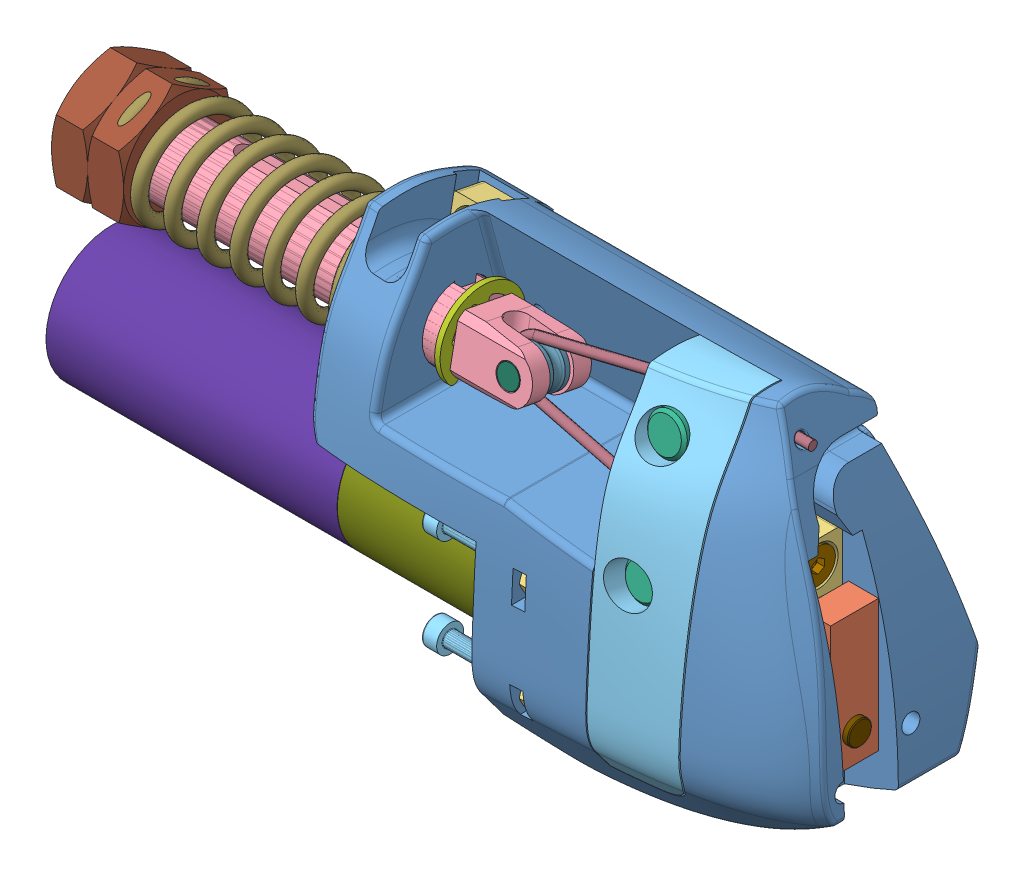
SolidWorks assembly a-antriebstrang-amax22-v05, configuration 01. Lengths in mm.
Overall size (136.53 64.51 41.42).
40 component instances, 22 part files, 63 mates.
Components (placement in the parent):
- a-motorträger-v01-1: a-motorträger-v01 [01] x (-1 0 0) z (0 0 -1) size (130.38 64.51 41.42)
  - p-halterreferenz-v02-1: p-halterreferenz-v02 [01] at (-8 0 0) x (0 0 -1) z (1 0 0) size (41.19 64.51 84.36)
  - z-jfm-0608-06-v01-1: z-jfm-0608-06-v01 [01] at (-23.3 0 0) x (-1 0 0) z (0 0 -1) size (6 12 12)
  - z-induktiv-sensor-v01-1: z-induktiv-sensor-v01 [01] at (29 21.9082 7.6275) x (1 0 0) z (0 0.190809 -0.981627) size (8 16 4.7)
  - z-induktiv-sensor-v01-2: z-induktiv-sensor-v01 [01] at (-25.5 8.63 4) x (0 0 -1) z (-1 0 0) size (8 16 4.7)
  - p-federstössel-v01-1: p-federstössel-v01 [01] at (77.9 27.8 -1.72) x (-1 0 0) z (0 -0.190809 0.981627) size (77 12 12)
  - p-halterdeckel-v01-1: p-halterdeckel-v01 [01] at (-8 0 0) x (0 0 -1) z (1 0 0) size (29.44 55.93 14.71)
  - z-passschraube-misumi-4-v01-1: z-passschraube-misumi-4-v01 [01] at (-13.1 35.2829 -8.5672) x (0 -0.190809 0.981627) z (-0.839411 -0.533511 -0.103704) size (18 6.5 6.5)
  - z-passschraube-misumi-4-v01-2: z-passschraube-misumi-4-v01 [01] at (-13.1 16.1412 -12.288) x (0 -0.190809 0.981627) z (-0.58333 0.797312 0.154982) size (18 6.5 6.5)
  - lock washer for shafts_din-3: lock washer for shafts_din [Lock washer DIN 6799 - 7] at (24 27.8 -1.72) x (0 0 1) z (-1 0 0) size (14.3 11.94 0.9)
  - hex nut style 1 gradeab_din-3: hex nut style 1 gradeab_din [Hexagon Nut ISO 4032 - M2.5 - W - N] at (-13.1 31.8991 8.8409) x (1 0 0) z (0 -0.190809 0.981627) size (5 5.77 2)
  - hex nut style 1 gradeab_din-4: hex nut style 1 gradeab_din [Hexagon Nut ISO 4032 - M2.5 - W - N] at (-13.1 12.7574 5.1202) x (1 0 0) z (0 -0.190809 0.981627) size (5 5.77 2)
  - socket countersunk head screw_din-3: socket countersunk head screw_din [DIN 7991 - M3 x 8 --- 4.8C] at (-30.15 20.63 0) size (8 5.7 5.7)
  - socket countersunk head screw_din-4: socket countersunk head screw_din [DIN 7991 - M3 x 8 --- 4.8C] at (33 34.5749 5.3527) x (0 -0.190809 0.981627) z (-0.981627 0.187303 0.036408) size (8 5.7 5.7)
  - p-oese-v01-1: p-oese-v01 [01] at (-25.5 37.4 0) size (3.5 4 4)
  - hex thin nut chamfered gradeab_din-3: hex thin nut chamfered gradeab_din [Hexagon Thin Nut ISO 4035 - M12 - N] at (74.9 27.8 -1.72) x (0 -0.006521 -0.999979) z (-1 0 0) size (18 20.78 6)
  - hex thin nut chamfered gradeab_din-4: hex thin nut chamfered gradeab_din [Hexagon Thin Nut ISO 4035 - M12 - N] at (80.9 27.8 -1.72) x (0 0 1) z (-1 0 0) size (18 20.78 6)
  - z-feder-febrotec-v01-1: z-feder-febrotec-v01 [01] at (40 28.171 -1.6479) x (1 0 0) z (0 -0.190809 0.981627) size (40.25 20.98 20.5)
  - p-seil-v02-1: p-seil-v02 [01] at (-16.85 -0.1381 -7.1506) x (-1 0 0) z (0 0.190809 -0.981627) size (48.5 39 1.5)
  - p-umlenkpulley-v06-1: p-umlenkpulley-v06 [01] at (-13.1 33.728 -0.5677) x (0 -0.190809 0.981627) z (-0.981627 0.187303 0.036408) size (3.6 7.15 7.15)
  - p-umlenkpulley-v06-4: p-umlenkpulley-v06 [01] at (-13.1 14.5863 -4.2885) x (0 -0.190809 0.981627) z (-0.997632 0.067518 0.013124) size (3.6 7.15 7.15)
  - p-umlenkpulley-v06-3: p-umlenkpulley-v06 [01] at (14.9 27.8 -1.72) x (0 -0.190809 0.981627) z (-0.981627 0.187303 0.036408) size (3.6 7.15 7.15)
  - parallel pin unhardened_din-3: parallel pin unhardened_din [Parallel Pin ISO 2338 - 4 h6 x 10 - St] at (14.9 28.754 -6.6281) x (0 -0.190809 0.981627) z (-0.981627 0.187303 0.036408) size (10 4 4)
- z-ec-amax22-gp22-c-v01-2: z-ec-amax22-gp22-c-v01 [01] x (-1 0 0) z (0 -0.173648 -0.984808) size (108.9 22 22)
  - z-getriebe-gp22c-v01-1: z-getriebe-gp22c-v01 [Standard] at origin size (53.85 22 22)
  - z-EC-max22-283856-v01-1: z-EC-max22-283856-v01 [01] at (39.05 0 0) size (65 22 22)
- p-motorpulley-v03-2: p-motorpulley-v03 [01] at (3.15 0 0) x (1 0 0) z (0 -0.173648 -0.984808) size (34 9 9)
- socket set screw flat point_din-2: socket set screw flat point_din [DIN 913 - M2 x 3-C] at (10.15 -0.7814 -4.4316) x (0 0.173648 0.984808) z (1 0 0) size (3 2 2)
- p-absolutmess-plättchen-v01-2: p-absolutmess-plättchen-v01 [01] at (36.2 0 0) x (0 0 1) z (-1 0 0) size (8 22 5)
- hex thin nut chamfered gradeab_din-6: hex thin nut chamfered gradeab_din [Hexagon Thin Nut ISO 4035 - M2.5 - C] at (-4 9 13) x (0 -0.5 0.866025) z (-1 0 0) size (5 5.77 1.6)
- hex thin nut chamfered gradeab_din-7: hex thin nut chamfered gradeab_din [Hexagon Thin Nut ISO 4035 - M2.5 - C] at (-4 -7.5 -13) x (0 0.5 0.866025) z (-1 0 0) size (5 5.77 1.6)
- hex thin nut chamfered gradeab_din-8: hex thin nut chamfered gradeab_din [Hexagon Thin Nut ISO 4035 - M2.5 - C] at (-4 9 -13) x (0 -0.5 0.866025) z (-1 0 0) size (5 5.77 1.6)
- hex thin nut chamfered gradeab_din-9: hex thin nut chamfered gradeab_din [Hexagon Thin Nut ISO 4035 - M2.5 - C] at (-4 -7.5 13) x (0 -1 0) z (-1 0 0) size (5 5.77 1.6)
- countersunk slotted raised head screw_din-5: countersunk slotted raised head screw_din [ISO 2010 - M2.5 x 10 --- 10C] at (9 6.5778 2.3941) x (-1 0 0) z (0 -0.859497 -0.51114) size (10.59 4.7 4.66)
- countersunk slotted raised head screw_din-6: countersunk slotted raised head screw_din [ISO 2010 - M2.5 x 10 --- 10C] at (9 -5.3623 4.4995) x (-1 0 0) z (0 -0.924225 -0.381849) size (10.59 4.7 4.66)
- countersunk slotted raised head screw_din-7: countersunk slotted raised head screw_din [ISO 2010 - M2.5 x 10 --- 10C] at (9 -1.2155 -6.8937) x (-1 0 0) z (0 -0.959089 0.283105) size (10.59 4.7 4.66)
- socket head cap screw_din-2: socket head cap screw_din [DIN 912 M2.5 x 16 --- 16C] at (-20.7 9 -13) size (18.5 4.5 4.5)
- socket head cap screw_din-3: socket head cap screw_din [DIN 912 M2.5 x 16 --- 16C] at (-20.7 -7.5 -13) x (1 0 0) z (0 -0.70701 -0.707203) size (18.5 4.5 4.5)
- socket head cap screw_din-4: socket head cap screw_din [DIN 912 M2.5 x 16 --- 16C] at (-20.7 9 13) size (18.5 4.5 4.5)
- socket head cap screw_din-5: socket head cap screw_din [DIN 912 M2.5 x 16 --- 16C] at (-20.7 -7.5 13) size (18.5 4.5 4.5)
Mates (geometry in assembly coordinates):
- Konzentrisch1: concentric aligned: cylinder of a-motorträger-v01-1/p-halterreferenz-v02-1 through (0 0 0) axis (-1 0 0) radius 11.5; cylinder of z-ec-amax22-gp22-c-v01-2/z-getriebe-gp22c-v01-1 through (-1.6 0 0) axis (-1 0 0) radius 11
- Deckungsgleich1: coincident anti-aligned: plane of a-motorträger-v01-1/p-halterreferenz-v02-1 through (0 0 0) normal (-1 0 0); plane of z-ec-amax22-gp22-c-v01-2/z-getriebe-gp22c-v01-1 through (0 -1.9101 -10.8329) normal (1 0 0)
- Deckungsgleich2: coincident anti-aligned: plane of a-motorträger-v01-1 through (0 0 0) normal (0 0 -1); plane of assembly through (0 0 0) normal (0 0 1)
- Deckungsgleich3: coincident aligned: plane of a-motorträger-v01-1; plane of assembly through (0 0 0) normal (0 1 0)
- Deckungsgleich4: coincident anti-aligned: plane of a-motorträger-v01-1 through (0 0 0) normal (-1 0 0); plane of assembly through (0 0 0) normal (1 0 0)
- Konzentrisch2: concentric anti-aligned: cylinder of z-ec-amax22-gp22-c-v01-2/z-getriebe-gp22c-v01-1 through (3.15 0 0) axis (1 0 0) radius 2; cylinder of p-motorpulley-v03-2 through (3.15 0 0) axis (-1 0 0) radius 2
- Deckungsgleich5: coincident anti-aligned: plane of z-ec-amax22-gp22-c-v01-2/z-getriebe-gp22c-v01-1 through (3.15 -3.4468 0.6078) normal (1 0 0); plane of p-motorpulley-v03-2 through (3.15 -4.4316 0.7814) normal (-1 0 0)
- Konzentrisch3: concentric anti-aligned: cylinder of p-motorpulley-v03-2 through (10.15 0 0) axis (0 0.173648 0.984808) radius 0.8; cylinder of socket set screw flat point_din-2 through (10.15 -2.9867 -16.9387) axis (0 -0.173648 -0.984808) radius 1
- Parallel2: parallel aligned: plane of z-ec-amax22-gp22-c-v01-2/z-getriebe-gp22c-v01-1 through (14.85 1.0423 -1.7069) normal (0 -0.173648 -0.984808); plane of p-motorpulley-v03-2 through (3.15 0 0) normal (0 -0.173648 -0.984808)
- Deckungsgleich7: coincident anti-aligned: plane of z-ec-amax22-gp22-c-v01-2/z-getriebe-gp22c-v01-1 through (14.85 1.0423 -1.7069) normal (0 -0.173648 -0.984808); plane of socket set screw flat point_din-2 through (10.15 -0.7529 -1.3904) normal (0 0.173648 0.984808)
- Parallel3: parallel anti-aligned: plane of a-motorträger-v01-1/p-halterreferenz-v02-1 through (42 0 -4.5) normal (0 0 1); plane of p-absolutmess-plättchen-v01-2 through (31.2 -5 -4) normal (0 0 -1)
- Abstand1: distance = 1 mm anti-aligned: plane of a-motorträger-v01-1/z-induktiv-sensor-v01-2 through (30.2 8.63 -4) normal (1 0 0); plane of p-absolutmess-plättchen-v01-2 through (31.2 0 0) normal (-1 0 0)
- Konzentrisch5: concentric aligned: cylinder of p-motorpulley-v03-2 through (3.15 0 0) axis (-1 0 0) radius 2; cylinder of p-absolutmess-plättchen-v01-2 through (31.2 0 0) axis (-1 0 0) radius 1.89
- Konzentrisch6: concentric anti-aligned: cylinder of a-motorträger-v01-1/p-halterreferenz-v02-1 through (-42.3814 -5.3623 4.4995) axis (1 0 0) radius 1.35; cylinder of z-ec-amax22-gp22-c-v01-2/z-getriebe-gp22c-v01-1 through (0 -5.3623 4.4995) axis (-1 0 0) radius 0.975
- Deckungsgleich8: coincident anti-aligned: plane of a-motorträger-v01-1/p-halterreferenz-v02-1 through (-4 0 0) normal (1 0 0); plane of hex thin nut chamfered gradeab_din-6 through (-4 11.5 14.4434) normal (-1 0 0)
- Konzentrisch25: concentric anti-aligned: cylinder of a-motorträger-v01-1/p-halterreferenz-v02-1 through (-41.8849 9 13) axis (1 0 0) radius 1.35; cylinder of hex thin nut chamfered gradeab_din-6 through (-2.4 9 13) axis (-1 0 0) radius 1.025
- Parallel13: parallel anti-aligned: plane of a-motorträger-v01-1/p-halterreferenz-v02-1 through (-1.9 6.4 14.5011) normal (0 1 0); plane of hex thin nut chamfered gradeab_din-6 through (-2.4 6.5 11.5566) normal (0 -1 0)
- Konzentrisch26: concentric anti-aligned: cylinder of a-motorträger-v01-1/p-halterreferenz-v02-1 through (-41.8849 -7.5 13) axis (1 0 0) radius 1.35; cylinder of hex thin nut chamfered gradeab_din-9 through (-2.4 -7.5 13) axis (-1 0 0) radius 1.025
- Deckungsgleich10: coincident anti-aligned: plane of a-motorträger-v01-1/p-halterreferenz-v02-1 through (-4 0 0) normal (1 0 0); plane of hex thin nut chamfered gradeab_din-9 through (-4 -7.5 15.8868) normal (-1 0 0)
- Parallel14: parallel anti-aligned: plane of a-motorträger-v01-1/p-halterreferenz-v02-1 through (-1.9 -10.1 14.5011) normal (0 1 0); plane of hex thin nut chamfered gradeab_din-9 through (-2.4 -10 14.4434) normal (0 -1 0)
- Konzentrisch27: concentric anti-aligned: cylinder of a-motorträger-v01-1/p-halterreferenz-v02-1 through (-41.8849 -7.5 -13) axis (1 0 0) radius 1.35; cylinder of hex thin nut chamfered gradeab_din-7 through (-2.4 -7.5 -13) axis (-1 0 0) radius 1.025
- Deckungsgleich12: coincident anti-aligned: plane of a-motorträger-v01-1/p-halterreferenz-v02-1 through (-4 0 0) normal (1 0 0); plane of hex thin nut chamfered gradeab_din-7 through (-4 -5 -14.4434) normal (-1 0 0)
- Parallel15: parallel anti-aligned: plane of a-motorträger-v01-1/p-halterreferenz-v02-1 through (-1.9 -10.1 -14.5011) normal (0 1 0); plane of hex thin nut chamfered gradeab_din-7 through (-2.4 -10 -14.4434) normal (0 -1 0)
- Konzentrisch28: concentric anti-aligned: cylinder of a-motorträger-v01-1/p-halterreferenz-v02-1 through (-41.8849 9 -13) axis (1 0 0) radius 1.35; cylinder of hex thin nut chamfered gradeab_din-8 through (-2.4 9 -13) axis (-1 0 0) radius 1.025
- Deckungsgleich14: coincident anti-aligned: plane of a-motorträger-v01-1/p-halterreferenz-v02-1 through (-4 0 0) normal (1 0 0); plane of hex thin nut chamfered gradeab_din-8 through (-4 11.5 -11.5566) normal (-1 0 0)
- Konzentrisch29: concentric aligned: cylinder of a-motorträger-v01-1/p-halterreferenz-v02-1 through (-42.3814 -5.3623 4.4995) axis (1 0 0) radius 1.35; cylinder of countersunk slotted raised head screw_din-6 through (24.875 -5.3623 4.4995) axis (1 0 0) radius 1.25
- Deckungsgleich16: coincident aligned: cone of a-motorträger-v01-1/p-halterreferenz-v02-1 through (8 -5.3623 4.4995) axis (-1 0 0); cone of countersunk slotted raised head screw_din-6 through (8 -5.3623 4.4995) axis (-1 0 0)
- Konzentrisch31: concentric aligned: cylinder of a-motorträger-v01-1/p-halterreferenz-v02-1 through (-42.3814 6.5778 2.3941) axis (1 0 0) radius 1.35; cylinder of countersunk slotted raised head screw_din-5 through (24.875 6.5778 2.3941) axis (1 0 0) radius 1.25
- Deckungsgleich17: coincident aligned: cone of a-motorträger-v01-1/p-halterreferenz-v02-1 through (8 6.5778 2.3941) axis (-1 0 0); cone of countersunk slotted raised head screw_din-5 through (8 6.5778 2.3941) axis (-1 0 0)
- Konzentrisch33: concentric aligned: cylinder of a-motorträger-v01-1/p-halterreferenz-v02-1 through (-42.3814 -1.2155 -6.8937) axis (1 0 0) radius 1.35; cylinder of countersunk slotted raised head screw_din-7 through (24.875 -1.2155 -6.8937) axis (1 0 0) radius 1.25
- Deckungsgleich18: coincident aligned: cone of a-motorträger-v01-1/p-halterreferenz-v02-1 through (8 -1.2155 -6.8937) axis (-1 0 0); cone of countersunk slotted raised head screw_din-7 through (8 -1.2155 -6.8937) axis (-1 0 0)
- Konzentrisch197: concentric anti-aligned: cylinder of a-motorträger-v01-1/p-halterreferenz-v02-1 through (-41.8849 -7.5 13) axis (1 0 0) radius 1.35; cylinder of socket head cap screw_din-5 through (-52.45 -7.5 13) axis (-1 0 0) radius 1.25
- Konzentrisch198: concentric anti-aligned: cylinder of a-motorträger-v01-1/p-halterreferenz-v02-1 through (-41.8849 9 13) axis (1 0 0) radius 1.35; cylinder of socket head cap screw_din-4 through (-52.45 9 13) axis (-1 0 0) radius 1.25
- Konzentrisch199: concentric anti-aligned: cylinder of a-motorträger-v01-1/p-halterreferenz-v02-1 through (-41.8849 -7.5 -13) axis (1 0 0) radius 1.35; cylinder of socket head cap screw_din-3 through (-52.45 -7.5 -13) axis (-1 0 0) radius 1.25
- Konzentrisch200: concentric anti-aligned: cylinder of a-motorträger-v01-1/p-halterreferenz-v02-1 through (-41.8849 9 -13) axis (1 0 0) radius 1.35; cylinder of socket head cap screw_din-2 through (-52.45 9 -13) axis (-1 0 0) radius 1.25
- Abstand2: distance = 8.2 mm anti-aligned: plane of a-motorträger-v01-1/p-halterreferenz-v02-1 through (-10 0 0) normal (-1 0 0); plane of socket head cap screw_din-4 through (-18.2 11.25 13) normal (1 0 0)
- Deckungsgleich84: coincident aligned: plane of socket head cap screw_din-2 through (-18.2 11.25 -13) normal (1 0 0); plane of socket head cap screw_din-4 through (-18.2 11.25 13) normal (1 0 0)
- Deckungsgleich85: coincident aligned: plane of socket head cap screw_din-4 through (-18.2 11.25 13) normal (1 0 0); plane of socket head cap screw_din-5 through (-18.2 -5.25 13) normal (1 0 0)
- Deckungsgleich86: coincident aligned: plane of socket head cap screw_din-3 through (-18.2 -9.0912 -11.4092) normal (1 0 0); plane of socket head cap screw_din-4 through (-18.2 11.25 13) normal (1 0 0)
- Konzentrisch305: concentric anti-aligned: cylinder of p-motorpulley-v03-2 through (10.15 0 0) axis (0 0.173648 -0.984808) radius 0.8; cylinder of ? through (10.15 -2.9867 16.9387) axis (0 -0.173648 0.984808) radius 1
- Parallel93: parallel anti-aligned: plane of a-motorträger-v01-1/p-halterreferenz-v02-1 through (42 0 4.5) normal (0 0 -1); plane of p-absolutmess-plättchen-v01-2 through (36.2 -5 4) normal (0 0 1)
- Konzentrisch306: concentric anti-aligned: cylinder of p-motorpulley-v03-2 through (3.15 0 0) axis (-1 0 0) radius 2; cylinder of p-absolutmess-plättchen-v01-2 through (36.2 0 0) axis (1 0 0) radius 1.89
- Konzentrisch307: concentric aligned: cylinder of a-motorträger-v01-1/p-halterreferenz-v02-1 through (-41.8849 9 -13) axis (1 0 0) radius 1.35; cylinder of ? through (-4.002 9 -13) axis (1 0 0) radius 1.025
- Parallel94: parallel anti-aligned: plane of a-motorträger-v01-1/p-halterreferenz-v02-1 through (-1.9 6.4 -14.5011) normal (0 1 0); plane of ? through (-4.002 6.5 -11.5566) normal (0 -1 0)
- Konzentrisch308: concentric aligned: cylinder of a-motorträger-v01-1/p-halterreferenz-v02-1 through (-41.8849 -7.5 -13) axis (1 0 0) radius 1.35; cylinder of ? through (-4.002 -7.5 -13) axis (1 0 0) radius 1.025
- Parallel95: parallel anti-aligned: plane of a-motorträger-v01-1/p-halterreferenz-v02-1 through (-1.9 -10.1 -14.5011) normal (0 1 0); plane of ? through (-4.002 -10 -14.4434) normal (0 -1 0)
- Konzentrisch309: concentric aligned: cylinder of a-motorträger-v01-1/p-halterreferenz-v02-1 through (-41.8849 -7.5 13) axis (1 0 0) radius 1.35; cylinder of ? through (-4.002 -7.5 13) axis (1 0 0) radius 1.025
- Parallel96: parallel anti-aligned: plane of a-motorträger-v01-1/p-halterreferenz-v02-1 through (-1.9 -10.1 14.5011) normal (0 1 0); plane of ? through (-4.002 -10 14.4434) normal (0 -1 0)
- Konzentrisch310: concentric aligned: cylinder of a-motorträger-v01-1/p-halterreferenz-v02-1 through (-41.8849 9 13) axis (1 0 0) radius 1.35; cylinder of ? through (-4.002 9 13) axis (1 0 0) radius 1.025
- Konzentrisch311: concentric aligned: cylinder of a-motorträger-v01-1/p-halterreferenz-v02-1 through (-42.3814 -5.3623 -4.4995) axis (1 0 0) radius 1.35; cylinder of ? through (24.875 -5.3623 -4.4995) axis (1 0 0) radius 1.25
- Deckungsgleich143: coincident aligned: cone of a-motorträger-v01-1/p-halterreferenz-v02-1 through (8 -5.3623 -4.4995) axis (-1 0 0); cone of ? through (8 -5.3623 -4.4995) axis (-1 0 0)
- Konzentrisch312: concentric aligned: cylinder of a-motorträger-v01-1/p-halterreferenz-v02-1 through (-42.3814 6.5778 -2.3941) axis (1 0 0) radius 1.35; cylinder of ? through (24.875 6.5778 -2.3941) axis (1 0 0) radius 1.25
- Deckungsgleich144: coincident aligned: cone of a-motorträger-v01-1/p-halterreferenz-v02-1 through (8 6.5778 -2.3941) axis (-1 0 0); cone of ? through (8 6.5778 -2.3941) axis (-1 0 0)
- Konzentrisch313: concentric aligned: cylinder of a-motorträger-v01-1/p-halterreferenz-v02-1 through (-42.3814 -1.2155 6.8937) axis (1 0 0) radius 1.35; cylinder of ? through (24.875 -1.2155 6.8937) axis (1 0 0) radius 1.25
- Deckungsgleich145: coincident aligned: cone of a-motorträger-v01-1/p-halterreferenz-v02-1 through (8 -1.2155 6.8937) axis (-1 0 0); cone of ? through (8 -1.2155 6.8937) axis (-1 0 0)
- Konzentrisch314: concentric anti-aligned: cylinder of a-motorträger-v01-1/p-halterreferenz-v02-1 through (-41.8849 -7.5 -13) axis (1 0 0) radius 1.35; cylinder of ? through (-52.45 -7.5 -13) axis (-1 0 0) radius 1.25
- Konzentrisch315: concentric anti-aligned: cylinder of a-motorträger-v01-1/p-halterreferenz-v02-1 through (-41.8849 9 -13) axis (1 0 0) radius 1.35; cylinder of socket head cap screw_din-2 through (-52.45 9 -13) axis (-1 0 0) radius 1.25
- Konzentrisch316: concentric anti-aligned: cylinder of a-motorträger-v01-1/p-halterreferenz-v02-1 through (-41.8849 -7.5 13) axis (1 0 0) radius 1.35; cylinder of ? through (-52.45 -7.5 13) axis (-1 0 0) radius 1.25
- Konzentrisch317: concentric anti-aligned: cylinder of a-motorträger-v01-1/p-halterreferenz-v02-1 through (-41.8849 9 13) axis (1 0 0) radius 1.35; cylinder of socket head cap screw_din-4 through (-52.45 9 13) axis (-1 0 0) radius 1.25
- Abstand11: distance = 8.2 mm anti-aligned: plane of a-motorträger-v01-1/p-halterreferenz-v02-1 through (-10 0 0) normal (-1 0 0); plane of socket head cap screw_din-2 through (-18.2 11.25 -13) normal (1 0 0)
- Deckungsgleich147: coincident aligned: plane of socket head cap screw_din-4 through (-18.2 11.25 13) normal (1 0 0); plane of socket head cap screw_din-2 through (-18.2 11.25 -13) normal (1 0 0)
- Deckungsgleich148: coincident aligned: plane of socket head cap screw_din-2 through (-18.2 11.25 -13) normal (1 0 0); plane of ? through (-18.2 -5.25 -13) normal (1 0 0)
- Deckungsgleich149: coincident aligned: plane of ? through (-18.2 -9.0912 11.4092) normal (1 0 0); plane of socket head cap screw_din-2 through (-18.2 11.25 -13) normal (1 0 0)
